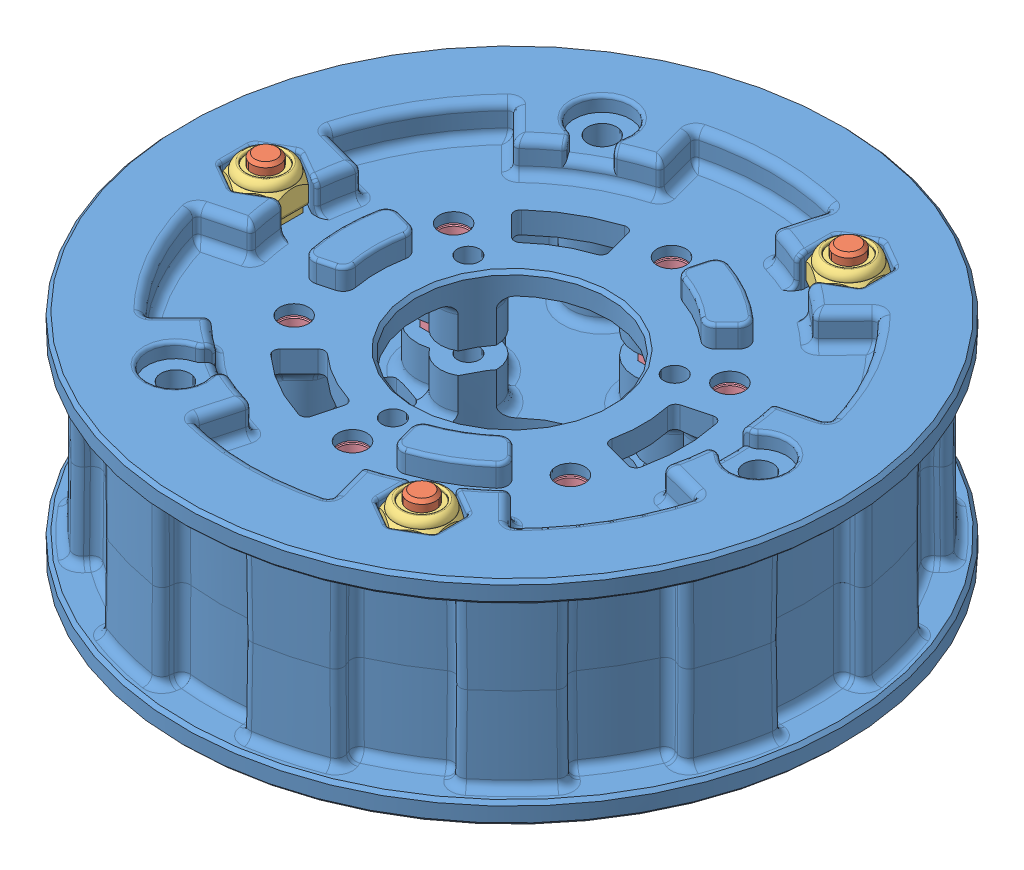
SolidWorks assembly Wheel Bering, configuration Default. Lengths in mm.
Overall size (134.42 33.99 134.42).
14 component instances, 4 part files, 0 mates.
Components (placement in the parent):
- 217-2588-001 Rev4-1: 217-2588-001 Rev4 [Default] at (-29.0417 2.9804 9.8781) size (98.4 19.7 98.4)
- 217-2588-001 Rev4-2: 217-2588-001 Rev4 [Default] at (-29.0417 25.2054 9.8781) x (0.5 0 -0.866025) z (-0.866025 0 -0.5) size (98.4 19.7 98.4)
- SCREW-832-1250-1: SCREW-832-1250 [Default] at (-65.8336 -1.7694 9.8781) x (0 1 0) z (0 0 1) size (33.96 7.92 7.92)
- NUT-832-NYLOCK-1: NUT-832-NYLOCK [Default] at (-65.8336 26.1617 9.8781) x (0.866025 0 -0.5) z (0.5 0 0.866025) size (10.2 5.86 8.12)
- NUT-832-NYLOCK-2: NUT-832-NYLOCK [Default] at (-10.6458 26.1617 -21.9846) x (0 0 1) z (-1 0 0) size (10.2 5.86 8.12)
- NUT-832-NYLOCK-3: NUT-832-NYLOCK [Default] at (-10.6458 26.1617 41.7408) x (-0.866025 0 -0.5) z (0.5 0 -0.866025) size (10.2 5.86 8.12)
- SCREW-832-1250-2: SCREW-832-1250 [Default] at (-10.6458 -1.7694 -21.9846) x (0 1 0) z (-0.866025 0 -0.5) size (33.96 7.92 7.92)
- SCREW-832-1250-3: SCREW-832-1250 [Default] at (-10.6458 -1.7694 41.7408) x (0 1 0) z (0.866025 0 -0.5) size (33.96 7.92 7.92)
- BEAM-0750-1: BEAM-0750 [Default] at (-49.664 13.9659 21.7843) x (0.5 0 -0.866025) z (0.866025 0 0.5) size (7.33 19.93 6.35)
- BEAM-0750-2: BEAM-0750 [Default] at (-29.0417 13.9659 33.6906) x (-0.5 0 -0.866025) z (0.866025 0 -0.5) size (7.33 19.93 6.35)
- BEAM-0750-3: BEAM-0750 [Default] at (-8.4195 13.9659 21.7843) x (-1 0 0) z (0 0 -1) size (7.33 19.93 6.35)
- BEAM-0750-4: BEAM-0750 [Default] at (-8.4195 13.9659 -2.0282) x (-0.5 0 0.866025) z (-0.866025 0 -0.5) size (7.33 19.93 6.35)
- BEAM-0750-5: BEAM-0750 [Default] at (-29.0417 13.9659 -13.9344) x (0.5 0 0.866025) z (-0.866025 0 0.5) size (7.33 19.93 6.35)
- BEAM-0750-6: BEAM-0750 [Default] at (-49.664 13.9659 -2.0282) size (7.33 19.93 6.35)
